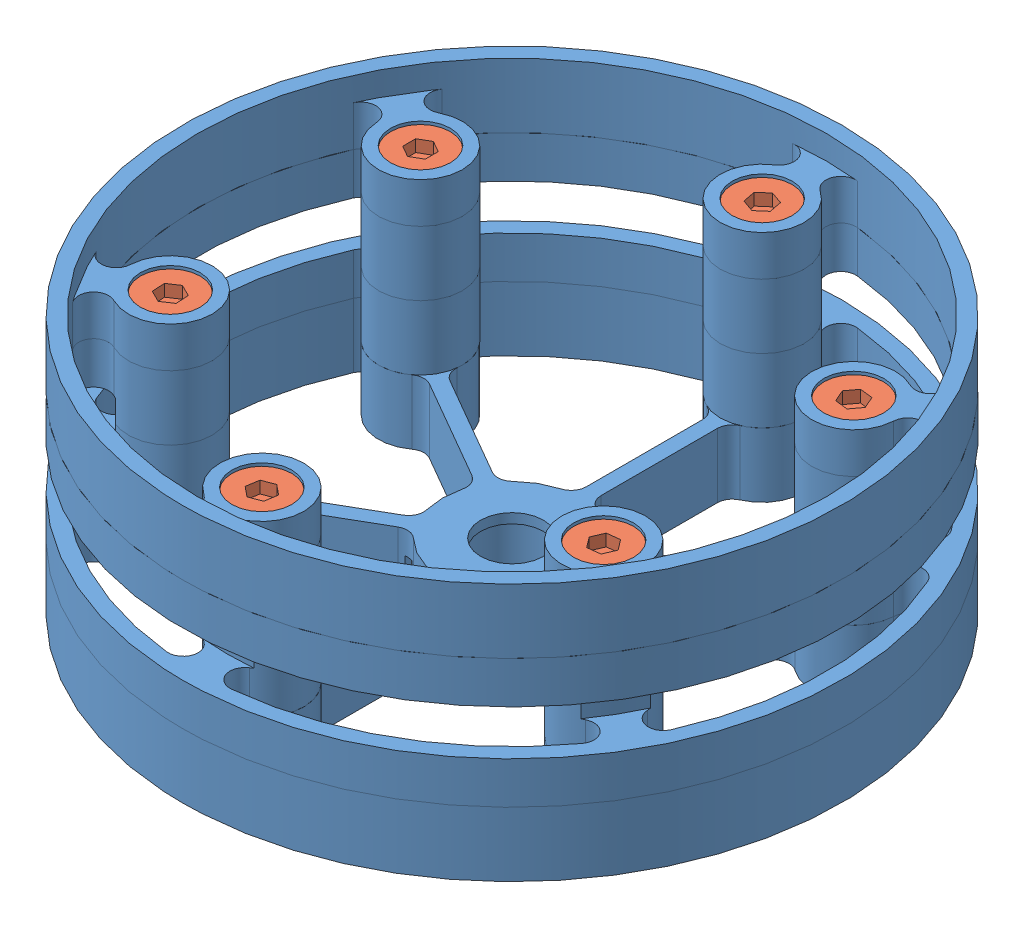
SolidWorks assembly wheel-free, configuration Default. Lengths in mm.
Overall size (60.11 17.8 60.11).
16 component instances, 3 part files, 27 mates.
Components (placement in the parent):
- wheel-1: wheel [Free inner] at origin size (44 4.3 44)
- wheel-2: wheel [Free middle] at (0 4.3 0) size (44 4.3 44)
- wheel-3: wheel [Free middle] at (0 12.9 0) x (-0.5 0 -0.866025) z (-0.866025 0 0.5) size (44 4.3 44)
- wheel-4: wheel [Free outer] at (0 12.9 0) size (44 4.3 44)
- countersunk-screw-m2-16mm-1: countersunk-screw-m2-16mm [Default] at (-14.4626 15.4 -8.35) x (0 -1 0) z (0 0 1) size (16 4 4)
- countersunk-screw-m2-16mm-2: countersunk-screw-m2-16mm [Default] at (0 15.4 -16.7) x (0 -1 0) z (0.188455 0 0.982082) size (16 4 4)
- countersunk-screw-m2-16mm-4: countersunk-screw-m2-16mm [Default] at (14.4626 15.4 -8.35) x (0 -1 0) z (0.395734 0 0.918365) size (16 4 4)
- countersunk-screw-m2-16mm-6: countersunk-screw-m2-16mm [Default] at (14.4626 15.4 8.35) x (0 -1 0) z (0.6 0 0.8) size (16 4 4)
- countersunk-screw-m2-16mm-8: countersunk-screw-m2-16mm [Default] at (0 15.4 16.7) x (0 -1 0) z (0.773678 0 0.63358) size (16 4 4)
- countersunk-screw-m2-16mm-10: countersunk-screw-m2-16mm [Default] at (-14.4626 15.4 8.35) x (0 -1 0) z (0.896211 0 0.443629) size (16 4 4)
- insert-m2-4mm-1: insert-m2-4mm [Default] at (-14.4626 1.5 8.35) size (3.2 3 3.18)
- insert-m2-4mm-2: insert-m2-4mm [Default] at (0 1.5 16.7) x (0.982082 0 -0.188455) z (0.188455 0 0.982082) size (3.2 3 3.18)
- insert-m2-4mm-3: insert-m2-4mm [Default] at (14.4626 1.5 8.35) x (0.918365 0 -0.395734) z (0.395734 0 0.918365) size (3.2 3 3.18)
- insert-m2-4mm-4: insert-m2-4mm [Default] at (14.4626 1.5 -8.35) x (0.8 0 -0.6) z (0.6 0 0.8) size (3.2 3 3.18)
- insert-m2-4mm-5: insert-m2-4mm [Default] at (0 1.5 -16.7) x (0.63358 0 -0.773678) z (0.773678 0 0.63358) size (3.2 3 3.18)
- insert-m2-4mm-6: insert-m2-4mm [Default] at (-14.4626 1.5 -8.35) x (0.443629 0 -0.896211) z (0.896211 0 0.443629) size (3.2 3 3.18)
Mates (geometry in assembly coordinates):
- Coincident1: coincident: plane of wheel-1 through (0 4.3 0) normal (0 1 0); plane of wheel-2 through (0 4.3 0) normal (0 -1 0)
- Concentric1: concentric: cylinder of wheel-2 through (14.4626 4.299 -8.35) axis (0 1 0) radius 1.1; cylinder of wheel-1 through (14.4626 -0.001 -8.35) axis (0 1 0) radius 1.65
- Concentric2: concentric: cylinder of wheel-2 through (-14.4626 4.299 8.35) axis (0 1 0) radius 1.1; cylinder of wheel-1 through (-14.4626 -0.001 8.35) axis (0 1 0) radius 1.65
- Coincident2: coincident: plane of wheel-2 through (0 8.6 0) normal (0 1 0); plane of wheel-3 through (0 8.6 0) normal (0 -1 0)
- Concentric3: concentric: cylinder of wheel-2 through (14.4626 4.299 8.35) axis (0 1 0) radius 1.1; cylinder of wheel-3 through (14.4626 12.901 8.35) axis (0 -1 0) radius 1.1
- Concentric4: concentric: cylinder of wheel-2 through (-14.4626 4.299 -8.35) axis (0 1 0) radius 1.1; cylinder of wheel-3 through (-14.4626 12.901 -8.35) axis (0 -1 0) radius 1.1
- Coincident3: coincident: plane of wheel-3 through (0 12.9 0) normal (0 1 0); plane of wheel-4 through (0 12.9 0) normal (0 -1 0)
- Concentric5: concentric: cylinder of wheel-3 through (14.4626 12.901 8.35) axis (0 -1 0) radius 1.1; cylinder of wheel-4 through (14.4626 15.6 8.35) axis (0 1 0) radius 1.1
- Concentric6: concentric: cylinder of wheel-3 through (-14.4626 12.901 -8.35) axis (0 -1 0) radius 1.1; cylinder of wheel-4 through (-14.4626 15.6 -8.35) axis (0 1 0) radius 1.1
- Coincident4: coincident: cone of wheel-4 through (-14.4626 15.3 -8.35) axis (0 -1 0); cone of countersunk-screw-m2-16mm-1 through (-14.4626 14.3 -8.35) axis (0 -1 0)
- Coincident5: coincident: cone of wheel-4 through (0 15.3 -16.7) axis (0 -1 0); cone of countersunk-screw-m2-16mm-2 through (0 14.3 -16.7) axis (0 -1 0)
- Coincident6: coincident: cone of wheel-4 through (14.4626 15.3 -8.35) axis (0 -1 0); cone of countersunk-screw-m2-16mm-4 through (14.4626 14.3 -8.35) axis (0 -1 0)
- Coincident7: coincident: cone of wheel-4 through (14.4626 15.3 8.35) axis (0 -1 0); cone of countersunk-screw-m2-16mm-6 through (14.4626 14.3 8.35) axis (0 -1 0)
- Coincident8: coincident: cone of wheel-4 through (0 15.3 16.7) axis (0 -1 0); cone of countersunk-screw-m2-16mm-8 through (0 14.3 16.7) axis (0 -1 0)
- Coincident9: coincident: cone of wheel-4 through (-14.4626 15.3 8.35) axis (0 -1 0); cone of countersunk-screw-m2-16mm-10 through (-14.4626 14.3 8.35) axis (0 -1 0)
- Concentric7: concentric: cylinder of wheel-1 through (-14.4626 -0.001 8.35) axis (0 1 0) radius 1.65; cylinder of insert-m2-4mm-1 through (-14.4626 3 8.35) axis (0 -1 0) radius 1
- Coincident10: coincident: plane of wheel-1 through (0 0 0) normal (0 -1 0); plane of insert-m2-4mm-1 through (-14.4626 0 8.35) normal (0 -1 0)
- Coincident11: coincident: plane of wheel-1 through (0 0 0) normal (0 -1 0); plane of insert-m2-4mm-2 through (0 0 16.7) normal (0 -1 0)
- Concentric8: concentric: cylinder of wheel-1 through (0 -0.001 16.7) axis (0 1 0) radius 1.65; cylinder of insert-m2-4mm-2 through (0 3 16.7) axis (0 -1 0) radius 1
- Coincident12: coincident: plane of wheel-1 through (0 0 0) normal (0 -1 0); plane of insert-m2-4mm-3 through (14.4626 0 8.35) normal (0 -1 0)
- Concentric9: concentric: cylinder of wheel-1 through (14.4626 -0.001 8.35) axis (0 1 0) radius 1.65; cylinder of insert-m2-4mm-3 through (14.4626 3 8.35) axis (0 -1 0) radius 1
- Coincident13: coincident: plane of wheel-1 through (0 0 0) normal (0 -1 0); plane of insert-m2-4mm-4 through (14.4626 0 -8.35) normal (0 -1 0)
- Concentric10: concentric: cylinder of wheel-1 through (14.4626 -0.001 -8.35) axis (0 1 0) radius 1.65; cylinder of insert-m2-4mm-4 through (14.4626 3 -8.35) axis (0 -1 0) radius 1
- Coincident14: coincident: plane of wheel-1 through (0 0 0) normal (0 -1 0); plane of insert-m2-4mm-5 through (0 0 -16.7) normal (0 -1 0)
- Concentric11: concentric: cylinder of wheel-1 through (0 -0.001 -16.7) axis (0 1 0) radius 1.65; cylinder of insert-m2-4mm-5 through (0 3 -16.7) axis (0 -1 0) radius 1
- Coincident15: coincident: plane of wheel-1 through (0 0 0) normal (0 -1 0); plane of insert-m2-4mm-6 through (-14.4626 0 -8.35) normal (0 -1 0)
- Concentric12: concentric: cylinder of wheel-1 through (-14.4626 -0.001 -8.35) axis (0 1 0) radius 1.65; cylinder of insert-m2-4mm-6 through (-14.4626 3 -8.35) axis (0 -1 0) radius 1
